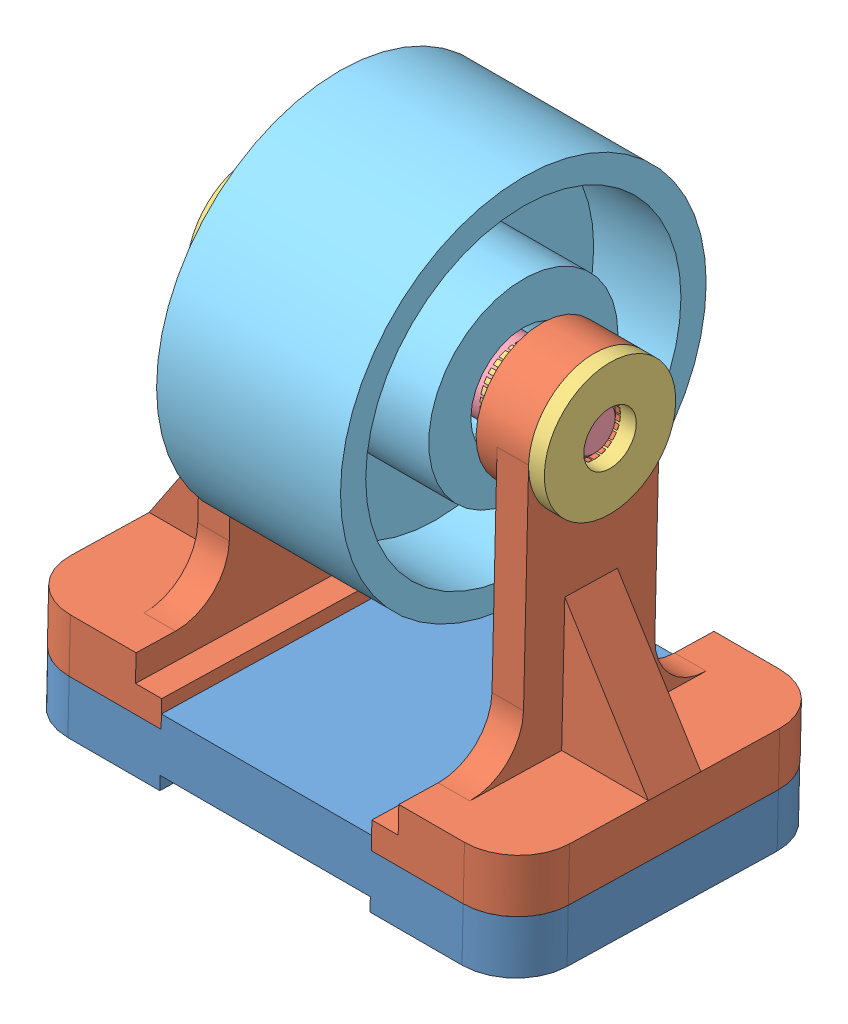
SolidWorks assembly Assem1, configuration Default. Lengths in mm.
Overall size (4.75 5.28 3.48).
7 component instances, 5 part files, 14 mates.
Components (placement in the parent):
- base-1: base [Default] at (-0.4796 2.4891 5.8875) x (1 0 0) z (0 0.024137 0.999709) size (4.75 0.62 3)
- braket-1: braket [Default] at (3.4454 5.9518 4.3035) x (0 0.024137 0.999709) z (-1 0 0) size (3 3.62 1.38)
- bushing-1: bushing [Default] at (3.5954 5.9518 4.3035) x (0 -0.924225 -0.381849) z (1 0 0) size (1.25 1.25 0.9)
- Part3-1: Part3 [Default] at (1.8954 5.9518 4.3035) x (0 0 -1) z (1 0 0) size (0.68 0.68 3.1)
- roller-1: roller [Default] at (2.7704 5.9518 4.3035) x (0 0 -1) z (1 0 0) size (3.48 3.48 1.75)
- braket-2: braket [Default] at (0.3454 5.9518 4.3035) x (0 -0.024137 -0.999709) z (1 0 0) size (3 3.62 1.38)
- bushing-2: bushing [Default] at (0.1954 5.9518 4.3035) x (0 -0.807313 0.590124) z (-1 0 0) size (1.25 1.25 0.9)
Mates (geometry in assembly coordinates):
- Coincident2: coincident anti-aligned: plane of base-1 through (2.8954 2.9165 2.8764) normal (1 0 0); plane of braket-1 through (2.8954 5.9518 4.3035) normal (-1 0 0)
- Coincident3: coincident anti-aligned: plane of base-1 through (4.2704 2.9165 2.8764) normal (0 0.999709 -0.024137); plane of braket-1 through (4.2704 2.9165 2.8764) normal (0 -0.999709 0.024137)
- Coincident4: coincident aligned: plane of base-1 through (-0.4796 2.4891 5.8875) normal (0 0.024137 0.999709); plane of braket-1 through (4.2704 2.9889 5.8755) normal (0 0.024137 0.999709)
- Coincident7: coincident anti-aligned: plane of base-1 through (0.8954 3.0415 2.8733) normal (-1 0 0); plane of braket-2 through (0.8954 5.9518 4.3035) normal (1 0 0)
- Coincident8: coincident aligned: plane of base-1 through (-0.4796 2.4891 5.8875) normal (0 0.024137 0.999709); plane of braket-2 through (-0.4796 3.4888 5.8634) normal (0 0.024137 0.999709)
- Coincident9: coincident anti-aligned: plane of base-1 through (0.8954 2.9165 2.8764) normal (0 0.999709 -0.024137); plane of braket-2 through (-0.4796 2.9889 5.8755) normal (0 -0.999709 0.024137)
- Concentric1: concentric anti-aligned: cylinder of Part3-1 through (0.3454 5.9518 4.3035) axis (1 0 0) radius 0.25; cylinder of braket-2 through (0.8454 5.9518 4.3035) axis (-1 0 0) radius 0.25
- Width1: width anti-aligned: plane of Part3-1 through (3.4454 5.9518 4.3035) normal (1 0 0); plane of Part3-1 through (0.3454 5.9518 4.3035) normal (-1 0 0); plane of braket-2 through (0.3454 5.9518 4.3035) normal (-1 0 0); plane of braket-1 through (3.4454 5.9518 4.3035) normal (1 0 0)
- Concentric2: concentric anti-aligned: cylinder of Part3-1 through (2.9454 5.9518 4.3035) axis (-1 0 0) radius 0.3375; cylinder of roller-1 through (1.8954 5.9518 4.3035) axis (1 0 0) radius 0.5
- Width2: width aligned: plane of roller-1 through (2.7704 5.9518 4.3035) normal (1 0 0); plane of roller-1 through (1.0204 5.9518 4.3035) normal (-1 0 0); plane of braket-2 through (0.6454 5.9518 4.3035) normal (1 0 0); plane of braket-1 through (3.1454 5.9518 4.3035) normal (-1 0 0)
- Concentric3: concentric aligned: cylinder of braket-1 through (2.9454 5.9518 4.3035) axis (1 0 0) radius 0.25; cylinder of bushing-1 through (2.6954 5.9518 4.3035) axis (1 0 0) radius 0.25
- Coincident10: coincident anti-aligned: plane of braket-1 through (3.4454 5.9518 4.3035) normal (1 0 0); plane of bushing-1 through (3.4454 5.9518 4.3035) normal (-1 0 0)
- Concentric4: concentric aligned: cylinder of braket-2 through (0.8454 5.9518 4.3035) axis (-1 0 0) radius 0.25; cylinder of bushing-2 through (1.0954 5.9518 4.3035) axis (-1 0 0) radius 0.25
- Coincident11: coincident anti-aligned: plane of braket-2 through (0.3454 5.9518 4.3035) normal (-1 0 0); plane of bushing-2 through (0.3454 5.9518 4.3035) normal (1 0 0)
